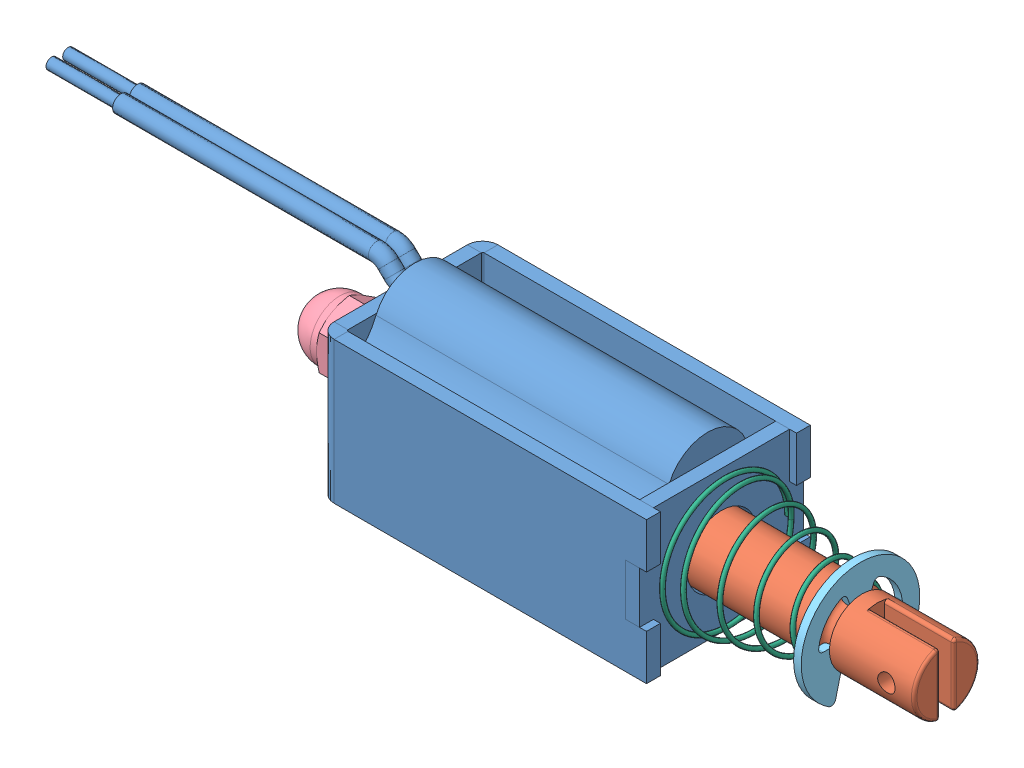
SolidWorks assembly JF-0530B, configuration Défaut. Lengths in mm.
Overall size (81.2 15.98 15).
6 component instances, 6 part files, 16 mates.
Components (placement in the parent):
- Coil-1: Coil [Défaut] at origin size (61.21 15.98 15)
- Plunger-1: Plunger [Défaut] at (34.9956 0 0) size (57.37 6 6)
- O-Ring-1: O-Ring [Défaut] at (-16.3403 0 0) x (0 -0.903 -0.42964) z (0 0.42964 -0.903) size (6 1.91 6)
- M3x0,5 Cap Nut-1: M3x0,5 Cap Nut [95514A101] at (-17.2928 0 0) x (0 0 -1) z (1 0 0) size (5.5 6.35 6)
- Circlip-1: Circlip [98543A113] at (26.7406 0 0) x (1 0 0) z (0 -1 0) size (0.7 10.85 10.07)
- Spring-1: Spring [1692K49] at (14.365 0 0) x (0 0 -1) z (0 -1 0) size (11.99 8.45 11.92)
Mates (geometry in assembly coordinates):
- Coïncidente1: coincident: line of Coil-1 through (0 26.825 13.095) axis (0 0 -1); plane of Plunger-1 through (34.9956 0 0) normal (0 0 1)
- Coïncidente2: coincident: line of Coil-1 through (0 26.825 13.095) axis (0 0 -1); plane of Plunger-1 through (34.9956 0 0) normal (0 1 0)
- Coïncidente3: coincident anti-aligned: line of Plunger-1 through (17.1734 -0.1194 0) axis (0 -1 0); line of O-Ring-1 through (0 5.2179 -18.0796) axis (0 0 1)
- Coaxiale1: concentric anti-aligned: cylinder of Plunger-1 through (-28.4374 0 0) axis (-1 0 0) radius 1.4605; cylinder of M3x0,5 Cap Nut-1 through (-21.0928 0 0) axis (1 0 0) radius 1.5
- Parallèle1: parallel aligned: plane of Plunger-1 through (28.6456 -3 -0.635) normal (0 0 1); plane of M3x0,5 Cap Nut-1 through (-19.9595 1.5877 2.75) normal (0 0 1)
- Tangent1: tangent anti-aligned: torus of O-Ring-1; plane of M3x0,5 Cap Nut-1 through (-17.2928 3.1754 0) normal (1 0 0)
- Coïncidente5: coincident: line of assembly; axis of Plunger-1 through (5.1264 25.0318 0) axis (0 1 0); axis of Circlip-1 through (27.0906 0 0) axis (-1 0 0)
- Coïncidente6: coincident aligned: plane of Plunger-1 through (34.9956 0 0) normal (0 0 1); plane of Circlip-1 through (26.7406 0 0) normal (0 0 1)
- Distance2: distance = 8.255 mm aligned: plane of Circlip-1 through (26.7406 0 0) normal (1 0 0); plane of Plunger-1 through (34.9956 0 0) normal (1 0 0)
- DistanceLimite1: limit distance = 49.9956 mm anti-aligned: plane of Coil-1 through (-15 -6.5 7.5) normal (-1 0 0); plane of Plunger-1 through (34.9956 0 0) normal (1 0 0)
- Coïncidente8: coincident anti-aligned: plane of Plunger-1 through (-17.2928 1.5 0) normal (-1 0 0); plane of M3x0,5 Cap Nut-1 through (-17.2928 3.1754 0) normal (1 0 0)
- Coïncidente9: coincident aligned: plane of Coil-1 through (14.365 0 0) normal (1 0 0); plane of Spring-1 through (14.365 0 0) normal (1 0 0)
- Coïncidente10: coincident anti-aligned: plane of Spring-1 through (14.365 0 0) normal (0 0 -1); plane of assembly through (0 0 0) normal (0 0 1)
- Coïncidente11: coincident anti-aligned: plane of Spring-1 through (14.365 0 0) normal (0 -1 0); plane of assembly through (0 0 0) normal (0 1 0)
- DistanceLimite2: limit distance = 12.0256 mm anti-aligned: plane of Circlip-1 through (26.3906 0 0) normal (-1 0 0); plane of Coil-1 through (14.365 0 0) normal (1 0 0)
- Parallel1: parallel anti-aligned: line of Coil-1 through (15 2.3495 -7.5) axis (0 1 0); line of Plunger-1 through (34.9956 2.5981 -0.889) axis (0 -1 0)
